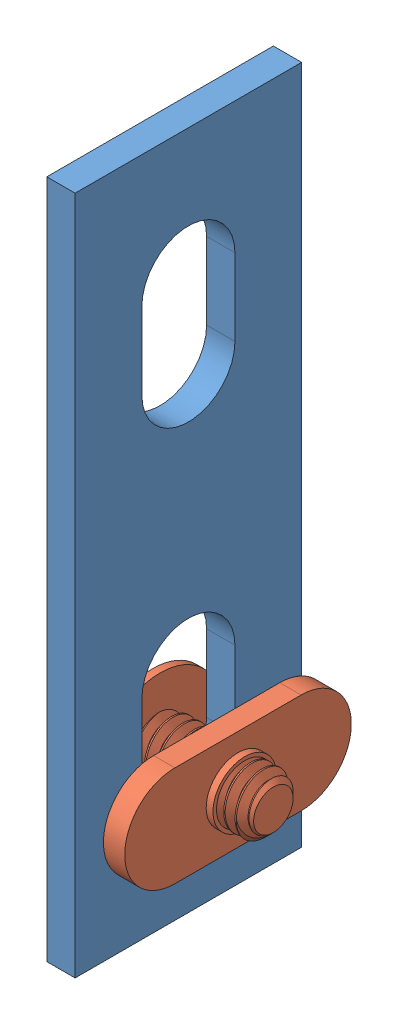
SolidWorks assembly Assem3, configuration Default. Lengths in mm.
Overall size (16.7 76.2 25.4).
2 component instances, 2 part files, 2 mates.
Components (placement in the parent):
- 2312N340_FLAT-SURFACE MACHINE BRACKET-1: 2312N340_FLAT-SURFACE MACHINE BRACKET [2312N34] at (38.2027 41.3392 53.1086) x (0 1 0) z (0 0 1) size (76.2 3.17 25.4)
- 47065T142_ALUMINUM T-SLOTTED FRAMING EXTRUSION-1: 47065T142_ALUMINUM T-SLOTTED FRAMING EXTRUSION [47065T142] at (35.0277 17.9839 53.1086) x (0 0 1) z (0 -1 0) size (25.4 16.7 13.87)
Mates (geometry in assembly coordinates):
- Coincident1: coincident: plane of 2312N340_FLAT-SURFACE MACHINE BRACKET-1 through (35.0277 41.3392 53.1086) normal (-1 0 0); plane of 47065T142_ALUMINUM T-SLOTTED FRAMING EXTRUSION-1 through (35.0277 19.4485 69.374) normal (1 0 0)
- Coincident2: coincident aligned: line of 2312N340_FLAT-SURFACE MACHINE BRACKET-1 through (35.0277 17.9839 53.1086) axis (1 0 0); line of 47065T142_ALUMINUM T-SLOTTED FRAMING EXTRUSION-1 through (34.1895 17.9839 53.1086) axis (1 0 0)
